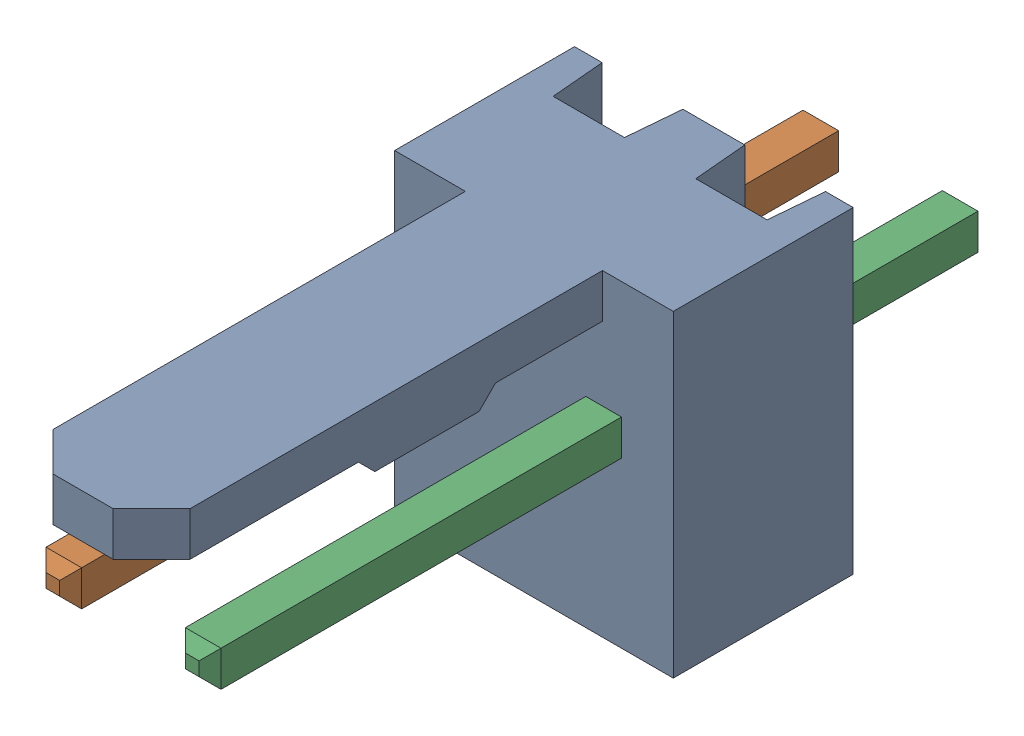
SolidWorks assembly Molex PCB 2 pin v2_5, configuration Default. Lengths in mm.
Overall size (5.08 5.79 14.92).
3 component instances, 2 part files, 0 mates.
Components (placement in the parent):
- BASE9710016_1-1: BASE9710016_1 [Default] at (2.54 2.895 -8.22) size (5.08 5.79 11.5)
- PINO9710016_1-1: PINO9710016_1 [Default] at (1.27 3.325 -0.72) size (0.65 0.65 14.2)
- PINO9710016_1-2: PINO9710016_1 [Default] at (3.81 3.325 -0.72) size (0.65 0.65 14.2)
